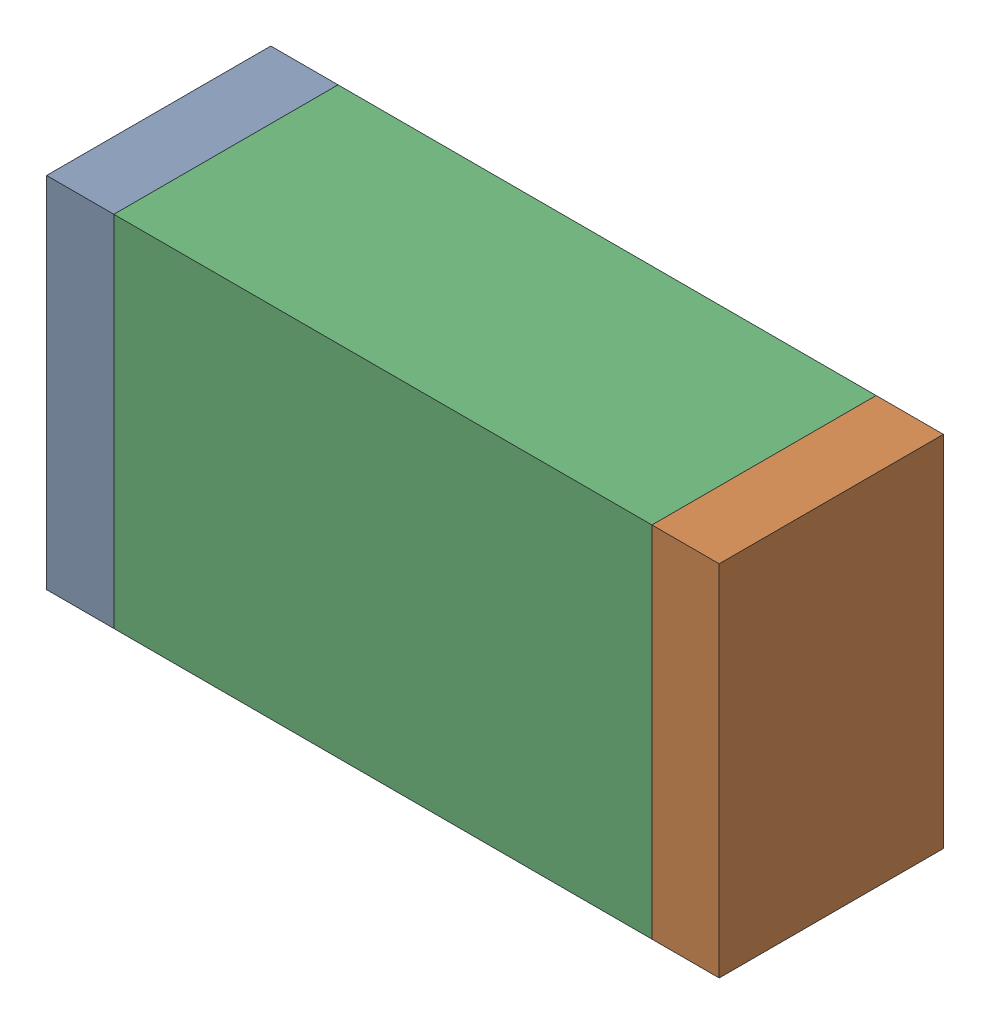
SolidWorks assembly R55, configuration Default. Lengths in mm.
Overall size (1.5 0.8 0.5).
6 component instances, 2 part files, 0 mates.
Components (placement in the parent):
- 836752496-1: 836752496 [Default] at (118.375 63.75 0) size (0.15 0.8 0.5)
  - Extruded_2-1: Extruded_2 [Default] at origin size (0.15 0.8 0.5)
- 836752496-2: 836752496 [Default] at (119.725 63.75 0) size (0.15 0.8 0.5)
  - Extruded_2-1: Extruded_2 [Default] at origin size (0.15 0.8 0.5)
- 836752368-1: 836752368 [Default] at (119.05 63.75 0) size (1.2 0.8 0.5)
  - Extruded-1: Extruded [Default] at origin size (1.2 0.8 0.5)
